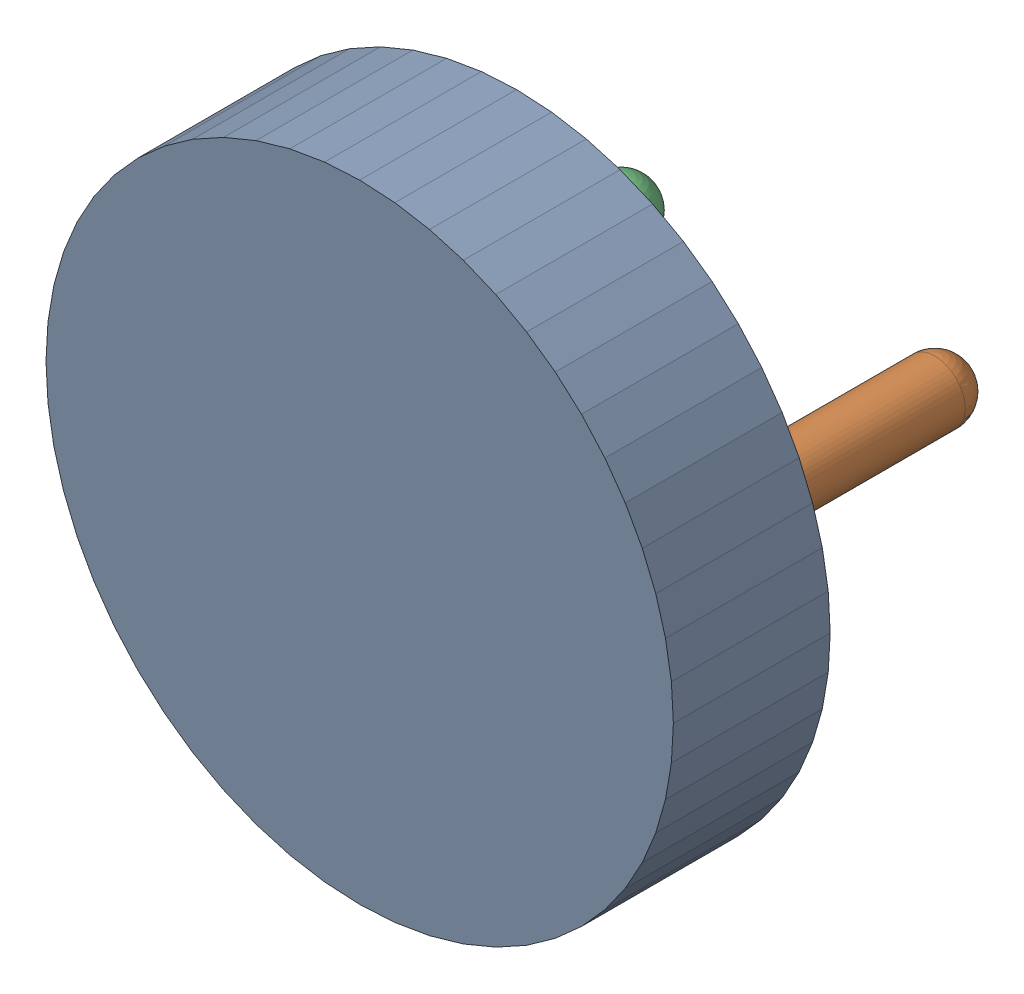
SolidWorks assembly BUZ1, configuration Défaut. Lengths in mm.
Overall size (12 12 8.59).
4 component instances, 3 part files, 0 mates.
Components (placement in the parent):
- Open CASCADE STEP translator 6.8 1.24.1-1: Open CASCADE STEP translator 6.8 1.24.1 [Défaut] at origin size (12 12 8.59)
  - Body_1_11-1: Body_1_11 [Défaut] at origin size (12 12 3)
  - Pin_1_8-1: Pin_1_8 [Défaut] x (0 -1 0) z (0 0 1) size (1.17 1.17 7.67)
  - Pin_2_8-1: Pin_2_8 [Défaut] at (-6 -6 0) x (0 -1 0) z (0 0 1) size (1.17 1.17 7.67)
